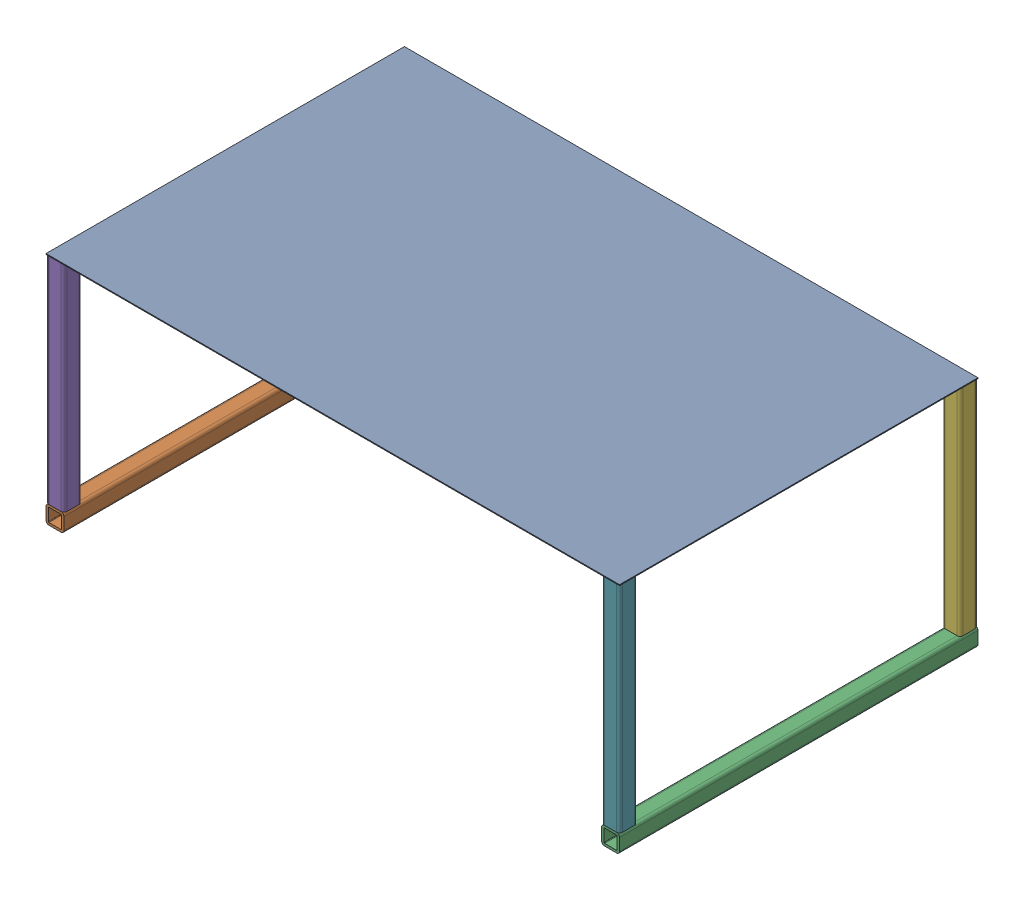
SolidWorks assembly Bottom Tray Assembly v2, configuration Default. Lengths in mm.
Overall size (406.4 165.71 254).
7 component instances, 3 part files, 19 mates.
Components (placement in the parent):
- Perforated Tray-1: Perforated Tray [92725T36] at (-209.6714 56.3674 72.3455) size (406.4 0.61 254)
- Tray Base-1: Tray Base [89825K319] at (-406.5214 -102.6874 72.3455) size (12.7 12.7 254)
- Tray Base-2: Tray Base [89825K319] at (-12.8214 -102.6874 72.3455) size (12.7 12.7 254)
- Tray Sides v2-1: Tray Sides v2 [89825K319] at (-406.5214 -20.1374 -48.3045) x (1 0 0) z (0 1 0) size (12.7 12.7 152.4)
- Tray Sides v2-2: Tray Sides v2 [89825K319] at (-406.5214 -20.1374 192.9955) x (1 0 0) z (0 1 0) size (12.7 12.7 152.4)
- Tray Sides v2-3: Tray Sides v2 [89825K319] at (-12.8214 -20.1374 -48.3045) x (1 0 0) z (0 1 0) size (12.7 12.7 152.4)
- Tray Sides v2-4: Tray Sides v2 [89825K319] at (-12.8214 -20.1374 192.9955) x (1 0 0) z (0 1 0) size (12.7 12.7 152.4)
Mates (geometry in assembly coordinates):
- Coincident16: coincident: plane of Perforated Tray-1 through (-412.8714 56.0626 199.3455) normal (-1 0 0); plane of Tray Base-1 through (-412.8714 -106.9736 187.0994) normal (-1 0 0)
- Coincident17: coincident: plane of Perforated Tray-1 through (-412.8714 56.0626 199.3455) normal (0 -1 0); plane of Tray Sides v2-4 through (-8.5351 56.0626 197.2818) normal (0 1 0)
- Coincident18: coincident: plane of Perforated Tray-1 through (-412.8714 56.0626 199.3455) normal (0 -1 0); plane of Tray Sides v2-2 through (-402.2351 56.0626 197.2818) normal (0 1 0)
- Coincident19: coincident: plane of Perforated Tray-1 through (-412.8714 56.0626 199.3455) normal (0 -1 0); plane of Tray Sides v2-1 through (-402.2351 56.0626 -44.0182) normal (0 1 0)
- Coincident20: coincident: plane of Perforated Tray-1 through (-412.8714 56.0626 199.3455) normal (0 -1 0); plane of Tray Sides v2-3 through (-8.5351 56.0626 -44.0182) normal (0 1 0)
- Coincident21: coincident: plane of Perforated Tray-1 through (-6.4714 56.0626 199.3455) normal (1 0 0); plane of Tray Sides v2-4 through (-6.4714 56.0626 197.2818) normal (1 0 0)
- Coincident22: coincident aligned: plane of Perforated Tray-1 through (-209.6714 56.3674 199.3455) normal (0 0 1); plane of Tray Sides v2-4 through (-8.5351 56.0626 199.3455) normal (0 0 1)
- Coincident23: coincident: plane of Perforated Tray-1 through (-6.4714 56.0626 199.3455) normal (1 0 0); plane of Tray Sides v2-3 through (-6.4714 56.0626 -44.0182) normal (1 0 0)
- Coincident24: coincident aligned: plane of Perforated Tray-1 through (-209.6714 56.3674 -54.6545) normal (0 0 -1); plane of Tray Sides v2-3 through (-8.5351 56.0626 -54.6545) normal (0 0 -1)
- Coincident25: coincident: plane of Tray Base-2 through (-8.5351 -96.3374 199.3455) normal (0 1 0); plane of Tray Sides v2-4 through (-8.5351 -96.3374 197.2818) normal (0 -1 0)
- Coincident26: coincident: plane of Tray Base-2 through (-8.5351 -106.9736 -54.6545) normal (0 0 -1); plane of Tray Sides v2-3 through (-8.5351 56.0626 -54.6545) normal (0 0 -1)
- Coincident27: coincident aligned: plane of Tray Base-2 through (-6.4714 -106.9736 199.3455) normal (1 0 0); plane of Tray Sides v2-3 through (-6.4714 56.0626 -44.0182) normal (1 0 0)
- Coincident28: coincident: plane of Perforated Tray-1 through (-412.8714 56.0626 199.3455) normal (-1 0 0); plane of Tray Sides v2-1 through (-412.8714 56.0626 -44.0182) normal (-1 0 0)
- Coincident29: coincident aligned: plane of Perforated Tray-1 through (-209.6714 56.3674 -54.6545) normal (0 0 -1); plane of Tray Sides v2-1 through (-402.2351 56.0626 -54.6545) normal (0 0 -1)
- Coincident30: coincident: plane of Perforated Tray-1 through (-412.8714 56.0626 199.3455) normal (-1 0 0); plane of Tray Sides v2-2 through (-412.8714 56.0626 197.2818) normal (-1 0 0)
- Coincident31: coincident aligned: plane of Perforated Tray-1 through (-209.6714 56.3674 199.3455) normal (0 0 1); plane of Tray Sides v2-2 through (-402.2351 56.0626 199.3455) normal (0 0 1)
- Coincident32: coincident: plane of Tray Base-1 through (-402.2351 -96.3374 199.3455) normal (0 1 0); plane of Tray Sides v2-1 through (-402.2351 -96.3374 -44.0182) normal (0 -1 0)
- Coincident33: coincident: plane of Tray Base-1 through (-412.8714 -106.9736 199.3455) normal (-1 0 0); plane of Tray Sides v2-1 through (-412.8714 56.0626 -44.0182) normal (-1 0 0)
- Coincident34: coincident aligned: plane of Tray Base-1 through (-402.2351 -106.9736 -54.6545) normal (0 0 -1); plane of Tray Sides v2-1 through (-402.2351 56.0626 -54.6545) normal (0 0 -1)
